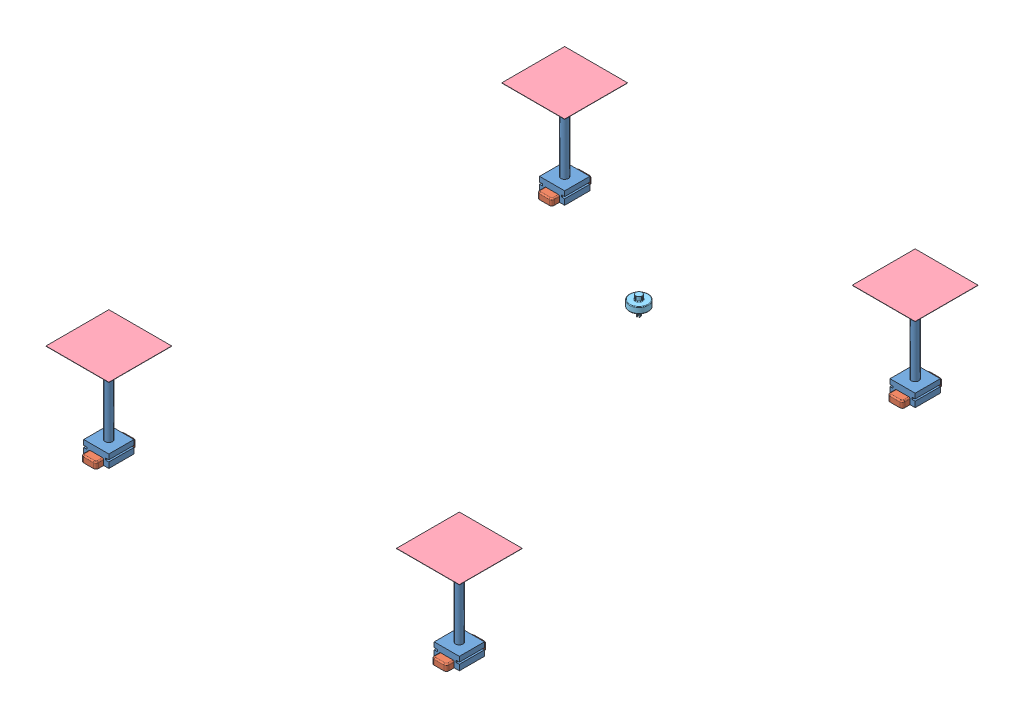
SolidWorks assembly Assem1, configuration Default. Lengths in mm.
Overall size (6576.8 1488.74 8252.61).
49 component instances, 7 part files, 16 mates.
Components (placement in the parent):
- pole-1: pole [Default] at (-167.9046 -238.5732 -645.8507) size (1000 1818.74 1000)
  - pilon-1: pilon [Default] at (750.6878 634.4701 2074.8363) size (400 1200 400)
  - fix-1: fix [Default] at (704.1878 324.4701 2336.3363) size (236 430 123)
    - screw - Copy-1: screw - Copy [Default] at origin size (83 330 83) (hidden)
    - Part3^fix-1: Part3^fix [Default] at origin size (236 100 123) (virtual)
    - screw2 - Copy - Copy-1: screw2 - Copy - Copy [Default] at (97.0846 0 0) size (83 330 83) (hidden)
  - fix-2: fix [Default] at (797.1878 324.4701 1813.3363) x (-1 0 0) z (0 0 -1) size (236 430 123)
    - screw - Copy-1: screw - Copy [Default] at origin size (83 330 83) (hidden)
    - Part3^fix-1: Part3^fix [Default] at origin size (236 100 123) (virtual)
    - screw2 - Copy - Copy-1: screw2 - Copy - Copy [Default] at (97.0846 0 0) size (83 330 83) (hidden)
  - pilon2-1: pilon2 [Default] at (750.6878 909.2097 2074.8363) x (-0.999521 0 0.03096) z (-0.03096 0 -0.999521) size (110 1000 110)
  - cap-2: cap [Default] at (750.6878 1909.2097 2074.8363) size (1000 264 1000)
- pole-2: pole [Default] at (-167.9046 -238.5732 6606.7606) size (1000 1818.74 1000)
  - pilon-1: pilon [Default] at (750.6878 634.4701 2074.8363) size (400 1200 400)
  - fix-1: fix [Default] at (704.1878 324.4701 2336.3363) size (236 430 123)
    - screw - Copy-1: screw - Copy [Default] at origin size (83 330 83) (hidden)
    - Part3^fix-1: Part3^fix [Default] at origin size (236 100 123) (virtual)
    - screw2 - Copy - Copy-1: screw2 - Copy - Copy [Default] at (97.0846 0 0) size (83 330 83) (hidden)
  - fix-2: fix [Default] at (797.1878 324.4701 1813.3363) x (-1 0 0) z (0 0 -1) size (236 430 123)
    - screw - Copy-1: screw - Copy [Default] at origin size (83 330 83) (hidden)
    - Part3^fix-1: Part3^fix [Default] at origin size (236 100 123) (virtual)
    - screw2 - Copy - Copy-1: screw2 - Copy - Copy [Default] at (97.0846 0 0) size (83 330 83) (hidden)
  - pilon2-1: pilon2 [Default] at (750.6878 909.2097 2074.8363) x (-0.999521 0 0.03096) z (-0.03096 0 -0.999521) size (110 1000 110)
  - cap-2: cap [Default] at (750.6878 1909.2097 2074.8363) size (1000 264 1000)
- arm-1: arm [Default] at (-1624.8808 1580.6365 3616.6194) size (300 300 300)
- pole-5: pole [Default] at (-5744.7067 -238.5732 6606.7606) size (1000 1818.74 1000)
  - pilon-1: pilon [Default] at (750.6878 634.4701 2074.8363) size (400 1200 400)
  - fix-1: fix [Default] at (704.1878 324.4701 2336.3363) size (236 430 123)
    - screw - Copy-1: screw - Copy [Default] at origin size (83 330 83) (hidden)
    - Part3^fix-1: Part3^fix [Default] at origin size (236 100 123) (virtual)
    - screw2 - Copy - Copy-1: screw2 - Copy - Copy [Default] at (97.0846 0 0) size (83 330 83) (hidden)
  - fix-2: fix [Default] at (797.1878 324.4701 1813.3363) x (-1 0 0) z (0 0 -1) size (236 430 123)
    - screw - Copy-1: screw - Copy [Default] at origin size (83 330 83) (hidden)
    - Part3^fix-1: Part3^fix [Default] at origin size (236 100 123) (virtual)
    - screw2 - Copy - Copy-1: screw2 - Copy - Copy [Default] at (97.0846 0 0) size (83 330 83) (hidden)
  - pilon2-1: pilon2 [Default] at (750.6878 909.2097 2074.8363) x (-0.999521 0 0.03096) z (-0.03096 0 -0.999521) size (110 1000 110)
  - cap-2: cap [Default] at (750.6878 1909.2097 2074.8363) size (1000 264 1000)
- pole-6: pole [Default] at (-5744.7067 -238.5732 -645.8507) size (1000 1818.74 1000)
  - pilon-1: pilon [Default] at (750.6878 634.4701 2074.8363) size (400 1200 400)
  - fix-1: fix [Default] at (704.1878 324.4701 2336.3363) size (236 430 123)
    - screw - Copy-1: screw - Copy [Default] at origin size (83 330 83) (hidden)
    - Part3^fix-1: Part3^fix [Default] at origin size (236 100 123) (virtual)
    - screw2 - Copy - Copy-1: screw2 - Copy - Copy [Default] at (97.0846 0 0) size (83 330 83) (hidden)
  - fix-2: fix [Default] at (797.1878 324.4701 1813.3363) x (-1 0 0) z (0 0 -1) size (236 430 123)
    - screw - Copy-1: screw - Copy [Default] at origin size (83 330 83) (hidden)
    - Part3^fix-1: Part3^fix [Default] at origin size (236 100 123) (virtual)
    - screw2 - Copy - Copy-1: screw2 - Copy - Copy [Default] at (97.0846 0 0) size (83 330 83) (hidden)
  - pilon2-1: pilon2 [Default] at (750.6878 909.2097 2074.8363) x (-0.999521 0 0.03096) z (-0.03096 0 -0.999521) size (110 1000 110)
  - cap-2: cap [Default] at (750.6878 1909.2097 2074.8363) size (1000 264 1000)
Mates (geometry in assembly coordinates):
- Parallel1: parallel: plane of pole-1/pilon-1 through (782.7831 595.8969 1628.9856) normal (0 0 1); plane of pole-2/pilon-1 through (782.7831 595.8969 8481.5969) normal (0 0 -1)
- Parallel2: parallel: plane of pole-1/pilon-1 through (382.7831 595.8969 1628.9856) normal (-1 0 0); plane of ? through (-5992.3988 595.8969 1628.9856) normal (-1 0 0)
- Parallel3: parallel: plane of pole-2/pilon-1 through (382.7831 595.8969 9736.9084) normal (-1 0 0); plane of ? through (-6303.6217 595.8969 9736.9084) normal (1 0 0)
- Distance4: distance = 0 mm: plane of pole-1/pilon-1 through (582.7831 595.8969 1428.9856) normal (0 1 0); plane of pole-2/pilon-1 through (582.7831 595.8969 8681.5969) normal (0 1 0)
- Distance5: distance = 0 mm: plane of pole-2/pilon-1 through (582.7831 595.8969 9536.9084) normal (0 1 0); plane of ? through (-6503.6217 595.8969 9536.9084) normal (0 1 0)
- Distance6: distance = 0 mm: plane of ? through (-6503.6217 595.8969 1428.9856) normal (0 1 0); plane of ? through (-6503.6217 595.8969 9536.9084) normal (0 1 0)
- Distance7: distance = 0 mm: plane of ? through (-6703.6217 595.8969 1628.9856) normal (-1 0 0); plane of ? through (-6703.6217 595.8969 9736.9084) normal (-1 0 0)
- Distance8: distance = 0 mm: plane of ? through (-6303.6217 595.8969 9736.9084) normal (0 0 1); plane of pole-2/pilon-1 through (782.7831 595.8969 9736.9084) normal (0 0 1)
- Distance9: distance = 0 mm: plane of ? through (-6303.6217 595.8969 1228.9856) normal (0 0 -1); plane of pole-1/pilon-1 through (782.7831 595.8969 1228.9856) normal (0 0 -1)
- Distance10: distance = 0 mm: plane of pole-2/pilon-1 through (782.7831 595.8969 8881.5969) normal (1 0 0); plane of pole-1/pilon-1 through (782.7831 595.8969 1628.9856) normal (1 0 0)
- Distance11: distance = 0 mm: plane of arm-1 through (-1624.8808 1680.6365 3616.6194) normal (0 1 0); plane of pole-1/cap-2 through (582.7831 1680.6365 1428.9856) normal (0 1 0)
- Distance12: distance = 0 mm: plane of pole-5/pilon-1 through (-4794.0189 595.8969 8881.5969) normal (0 0 1); plane of pole-2/pilon-1 through (782.7831 595.8969 8881.5969) normal (0 0 1)
- Distance13: distance = 0 mm: plane of pole-2/pilon-1 through (582.7831 595.8969 8681.5969) normal (0 1 0); plane of pole-5/pilon-1 through (-4994.0189 595.8969 8681.5969) normal (0 1 0)
- Distance14: distance = 0 mm: plane of pole-6/pilon-1 through (-4994.0189 595.8969 1428.9856) normal (0 1 0); plane of pole-1/pilon-1 through (582.7831 595.8969 1428.9856) normal (0 1 0)
- Distance15: distance = 0 mm: plane of pole-1/pilon-1 through (782.7831 595.8969 1228.9856) normal (0 0 -1); plane of pole-6/pilon-1 through (-4794.0189 595.8969 1228.9856) normal (0 0 -1)
- Distance16: distance = 0 mm: plane of pole-6/pilon-1 through (-5194.0189 595.8969 1628.9856) normal (-1 0 0); plane of pole-5/pilon-1 through (-5194.0189 595.8969 8881.5969) normal (-1 0 0)
